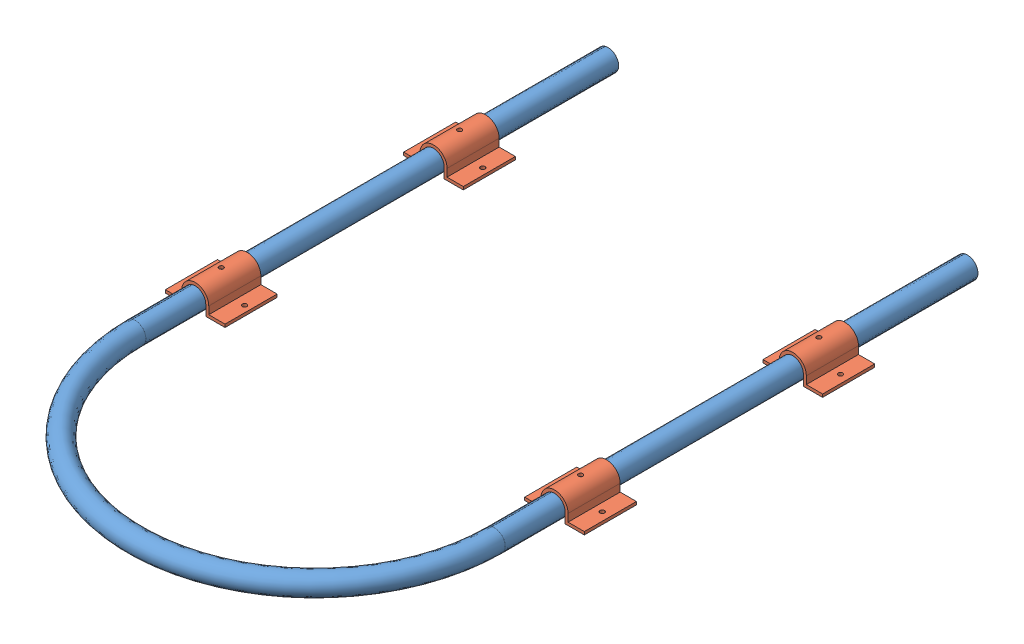
SolidWorks assembly Support Ring Assembly, configuration Default. Lengths in mm.
Overall size (562.74 32.45 890.52).
5 component instances, 2 part files, 6 mates.
Components (placement in the parent):
- Round Bar-2: Round Bar [Default] at (0 0 -67.5558) size (511.05 28.45 890.52)
- circular bracket-2: circular bracket [Default] at (241.3 -10.224 -217.9672) size (80.14 32.45 70)
- circular bracket-3: circular bracket [Default] at (-241.3 -10.224 -147.9672) x (-1 0 0) z (0 0 -1) size (80.14 32.45 70)
- circular bracket-4: circular bracket [Default] at (241.3 -10.224 -537.9955) size (80.14 32.45 70)
- circular bracket-5: circular bracket [Default] at (-241.3 -10.224 -467.9955) x (-1 0 0) z (0 0 -1) size (80.14 32.45 70)
Mates (geometry in assembly coordinates):
- Coincident1: coordinate: point of Round Bar-2
- Concentric2: concentric aligned: cylinder of Round Bar-2 through (241.3 0 -67.5558) axis (0 0 -1) radius 14.224; cylinder of circular bracket-2 through (241.3 0 -217.9672) axis (0 0 -1) radius 14.224
- Parallel1: parallel anti-aligned: plane of circular bracket-2 through (255.524 -14.224 -147.9672) normal (0 -1 0)
- Concentric4: concentric aligned: cylinder of Round Bar-2 through (241.3 0 -67.5558) axis (0 0 -1) radius 14.224; cylinder of circular bracket-4 through (241.3 0 -537.9955) axis (0 0 -1) radius 14.224
- Parallel3: parallel anti-aligned: plane of circular bracket-4 through (255.524 -14.224 -467.9955) normal (0 -1 0)
- Concentric5: concentric aligned: cylinder of Round Bar-2 through (-241.3 0 -702.5558) axis (0 0 1) radius 14.224; cylinder of circular bracket-3 through (-241.3 0 -147.9672) axis (0 0 1) radius 14.224
